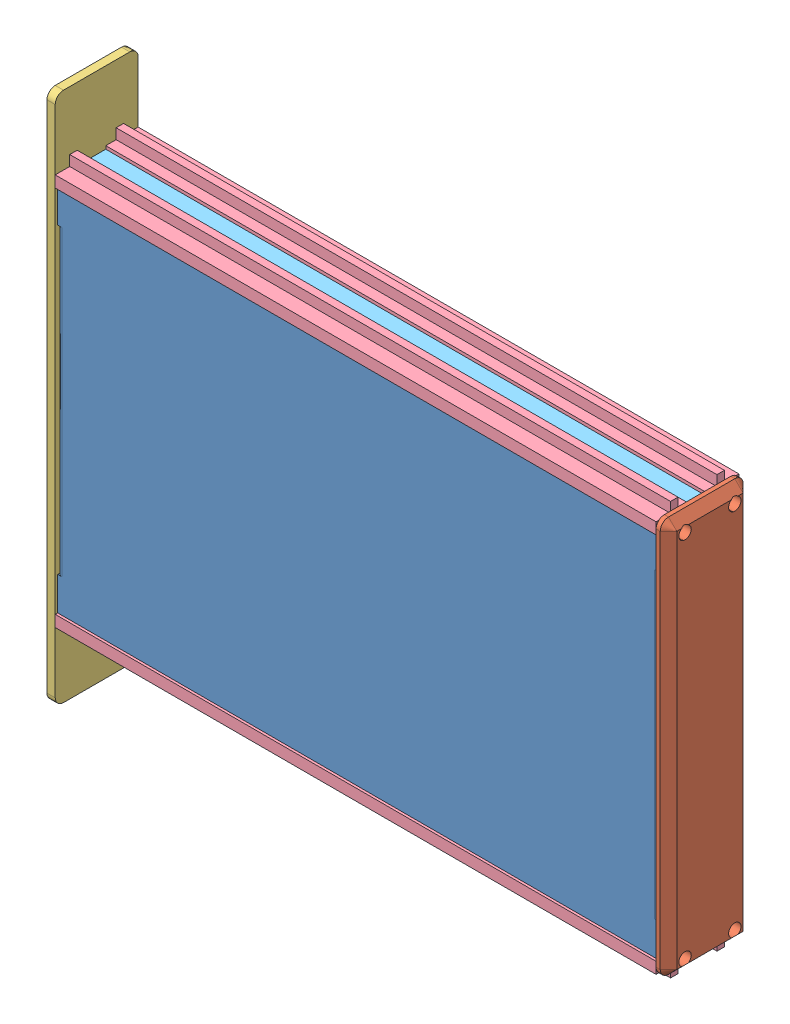
SolidWorks assembly kasten, configuration Standard. Lengths in mm.
Overall size (150 128 20).
10 component instances, 5 part files, 29 mates.
Components (placement in the parent):
- loch-1: loch [Standard] at (16.0111 29.8148 0) size (145 93 6)
- loch-2: loch [Standard] at (-22.5783 29.8148 -17.8) x (-1 0 0) z (0 0 -1) size (145 93 6)
- kiste-h-1: kiste-h [Standard] at (69.2164 36.035 -8.9) x (0 0 -1) z (1 0 0) size (20 95.6 3)
- kiste-f-2: kiste-f [Standard] at (-77.7836 36.035 -8.2564) x (0 0 -1) z (1 0 0) size (20 128 2)
- schiene-1: schiene [Standard] at (-75.7836 74.4356 -13.3248) x (0 0 -1) z (1 0 0) size (7.8 13.3 145)
- schiene-2: schiene [Standard] at (-75.7836 -2.3657 -4.4752) x (0 0 1) z (1 0 0) size (7.8 13.3 145)
- schiene-3: schiene [Standard] at (69.2164 74.4356 -4.4752) x (0 0 1) z (-1 0 0) size (7.8 13.3 145)
- schiene-4: schiene [Standard] at (69.2164 -2.3657 -13.3248) x (0 0 -1) z (-1 0 0) size (7.8 13.3 145)
- loch2-1: loch2 [Standard] at (-3.2836 82.595 -8.9) x (1 0 0) z (0 -1 0) size (145 7.6 0.5)
- loch2-2: loch2 [Standard] at (-3.2836 -10.025 -8.9) x (1 0 0) z (0 -1 0) size (145 7.6 0.5)
Mates (geometry in assembly coordinates):
- Deckungsgleich8: coincident anti-aligned: plane of loch-2 through (69.2164 -0.465 -12.3) normal (1 0 0); plane of kiste-h-1 through (69.2164 -11.765 1.1) normal (-1 0 0)
- Deckungsgleich9: coincident anti-aligned: plane of loch-1 through (69.2164 -0.465 -5.5) normal (1 0 0); plane of kiste-h-1 through (69.2164 -11.765 1.1) normal (-1 0 0)
- Deckungsgleich12: coincident anti-aligned: plane of loch-1 through (-72.7836 82.535 0.5) normal (0 1 0); plane of schiene-3 through (69.2164 82.535 0.5) normal (0 -1 0)
- Deckungsgleich13: coincident anti-aligned: plane of loch-1 through (-72.7836 -10.465 0.5) normal (0 0 1); plane of schiene-3 through (69.2164 80.585 0.5) normal (0 0 -1)
- Deckungsgleich14: coincident aligned: plane of loch-1 through (69.2164 -0.465 -5.5) normal (1 0 0); plane of schiene-3 through (69.2164 72.535 -6.7) normal (1 0 0)
- Deckungsgleich15: coincident anti-aligned: plane of loch-2 through (66.2164 -10.465 -18.3) normal (0 0 -1); plane of schiene-1 through (-75.7836 80.585 -18.3) normal (0 0 1)
- Deckungsgleich16: coincident anti-aligned: plane of loch-2 through (66.2164 82.535 -18.3) normal (0 1 0); plane of schiene-1 through (-75.7836 82.535 -18.3) normal (0 -1 0)
- Deckungsgleich17: coincident aligned: plane of loch-2 through (69.2164 -0.465 -12.3) normal (1 0 0); plane of schiene-1 through (69.2164 72.535 -11.1) normal (1 0 0)
- Deckungsgleich18: coincident anti-aligned: plane of loch-1 through (-72.7836 -10.465 0.5) normal (0 -1 0); plane of schiene-2 through (-75.7836 -10.465 0.5) normal (0 1 0)
- Deckungsgleich19: coincident anti-aligned: plane of loch-2 through (66.2164 -10.465 -18.3) normal (0 -1 0); plane of schiene-4 through (69.2164 -10.465 -18.3) normal (0 1 0)
- Deckungsgleich20: coincident anti-aligned: plane of loch-1 through (-72.7836 -10.465 0.5) normal (0 0 1); plane of schiene-2 through (-75.7836 -8.515 0.5) normal (0 0 -1)
- Deckungsgleich21: coincident anti-aligned: plane of loch-2 through (66.2164 -10.465 -18.3) normal (0 0 -1); plane of schiene-4 through (69.2164 -8.515 -18.3) normal (0 0 1)
- Deckungsgleich23: coincident aligned: plane of loch-2 through (-75.7836 -0.465 -12.3) normal (-1 0 0); plane of schiene-4 through (-75.7836 -0.465 -11.1) normal (-1 0 0)
- Deckungsgleich27: coincident aligned: plane of loch-1 through (-75.7836 -0.465 -5.5) normal (-1 0 0); plane of schiene-2 through (-75.7836 -0.465 -6.7) normal (-1 0 0)
- Deckungsgleich30: coincident aligned: axis of kiste-h-1; axis of schiene-1
- Deckungsgleich31: coincident anti-aligned: axis of kiste-h-1; axis of schiene-4
- Deckungsgleich32: coincident anti-aligned: axis of kiste-h-1; axis of schiene-3
- Deckungsgleich33: coincident aligned: axis of kiste-h-1; axis of schiene-2
- Deckungsgleich34: coincident anti-aligned: axis of kiste-f-2; axis of schiene-3
- Deckungsgleich35: coincident aligned: axis of kiste-f-2; axis of schiene-1
- Deckungsgleich36: coincident aligned: axis of kiste-f-2; axis of schiene-2
- Deckungsgleich37: coincident anti-aligned: axis of kiste-f-2; axis of schiene-4
- Deckungsgleich38: coincident anti-aligned: plane of loch-1 through (-75.7836 -0.465 -5.5) normal (-1 0 0); plane of kiste-f-2 through (-75.7836 -27.965 1.1) normal (1 0 0)
- Deckungsgleich39: coincident anti-aligned: plane of schiene-3 through (69.2164 79.0851 -5.1) normal (0 0 -1); plane of loch2-1 through (-75.7836 82.095 -5.1) normal (0 0 1)
- Deckungsgleich40: coincident anti-aligned: plane of schiene-3 through (69.2164 82.595 -15.2693) normal (0 -1 0); plane of loch2-1 through (-75.7836 82.595 -12.7) normal (0 1 0)
- Deckungsgleich41: coincident anti-aligned: plane of schiene-2 through (-75.7836 -7.0152 -5.1) normal (0 0 -1); plane of loch2-2 through (-75.7836 -10.525 -5.1) normal (0 0 1)
- Deckungsgleich42: coincident anti-aligned: plane of schiene-4 through (69.2164 -10.525 -2.5307) normal (0 1 0); plane of loch2-2 through (-75.7836 -10.525 -12.7) normal (0 -1 0)
- Deckungsgleich43: coincident anti-aligned: plane of kiste-f-2 through (-75.7836 -27.965 1.1) normal (1 0 0); plane of loch2-2 through (-75.7836 -10.525 -5.1) normal (-1 0 0)
- Deckungsgleich44: coincident anti-aligned: plane of kiste-f-2 through (-75.7836 -27.965 1.1) normal (1 0 0); plane of loch2-1 through (-75.7836 82.095 -5.1) normal (-1 0 0)
